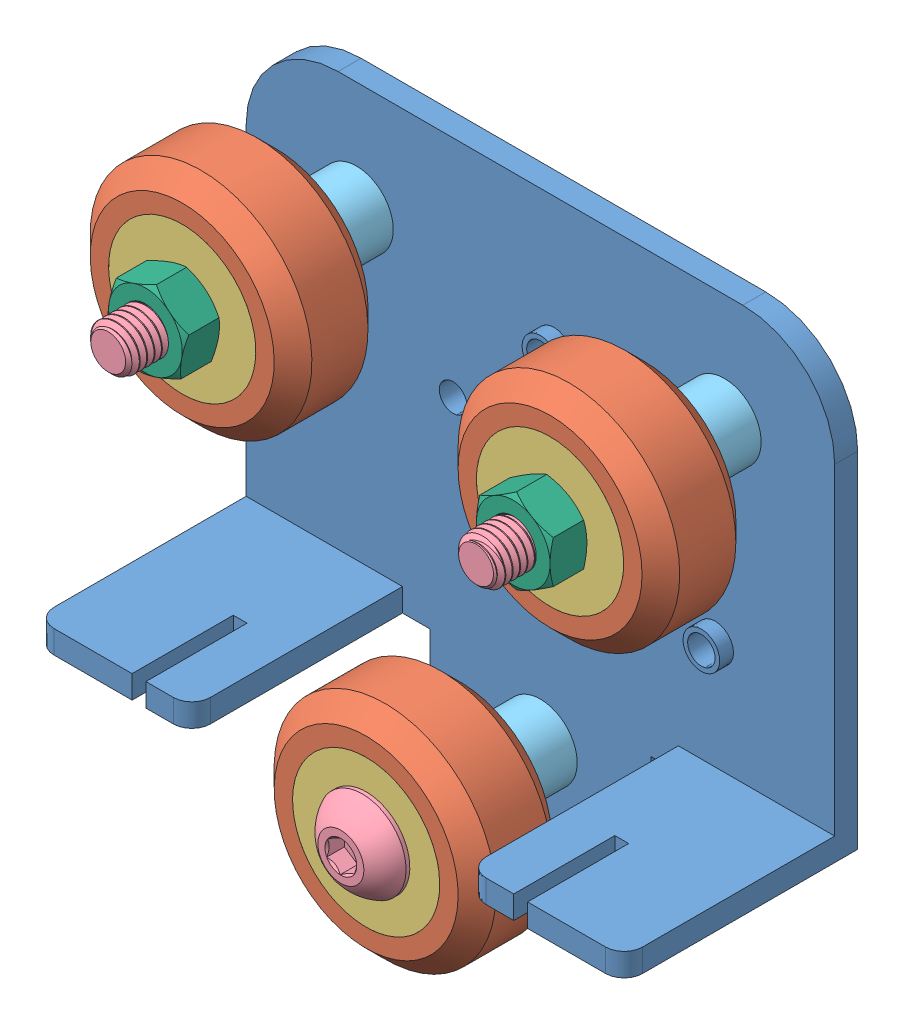
SolidWorks assembly extruder_x_assembly, configuration Default. Lengths in mm.
Overall size (67.79 70.29 30.09).
22 component instances, 6 part files, 12 mates.
Components (placement in the parent):
- E-Plate (Hot end plate)-1: E-Plate (Hot end plate) [Default] at origin size (64 64.1 29.9)
- roller_screw_assembly-4: roller_screw_assembly [2.5mm_gap] at (20 11.85 15.1) x (-1 0 0) z (0 0 -1) size (24.1 24.1 24.37)
  - roller_rubber-1: roller_rubber [Default] at origin size (24.1 24.1 10.2)
  - Bearing for Roller-1: Bearing for Roller [Default] at (0 0 3.1) x (0.970422 -0.241413 0) z (0 0 1) size (16 16 2)
  - Bearing for Roller-2: Bearing for Roller [Default] at (0 0 -5.1) x (0.995973 0.089651 0) z (0 0 1) size (16 16 2)
  - 92095A211_Button Head Hex Drive Screw-1: 92095A211_Button Head Hex Drive Screw [92095A211] at (0 0 19.1) x (-0.966026 0.258445 0) z (0 0 1) size (9.5 9.5 17.99)
  - Roller Spacer-1: Roller Spacer [long] at (0 0 5.1) x (0.816952 -0.576706 0) z (0 0 1) size (8 8 8.75)
- roller_screw_assembly-5: roller_screw_assembly [2.5mm_gap] at (-20 11.85 15.1) x (0.382683 -0.92388 0) z (0 0 -1) size (24.1 24.1 24.37)
  - roller_rubber-1: roller_rubber [Default] at origin size (24.1 24.1 10.2)
  - Bearing for Roller-1: Bearing for Roller [Default] at (0 0 3.1) x (0.970422 -0.241413 0) z (0 0 1) size (16 16 2)
  - Bearing for Roller-2: Bearing for Roller [Default] at (0 0 -5.1) x (0.995973 0.089651 0) z (0 0 1) size (16 16 2)
  - 92095A211_Button Head Hex Drive Screw-1: 92095A211_Button Head Hex Drive Screw [92095A211] at (0 0 19.1) x (-0.966026 0.258445 0) z (0 0 1) size (9.5 9.5 17.99)
  - Roller Spacer-1: Roller Spacer [long] at (0 0 5.1) x (0.816952 -0.576706 0) z (0 0 1) size (8 8 8.75)
- roller_screw_assembly-6: roller_screw_assembly [normal] at (0 -28.35 15.1) x (0.97681 0.214109 0) z (0 0 1) size (24.1 24.1 21.87)
  - roller_rubber-1: roller_rubber [Default] at origin size (24.1 24.1 10.2)
  - Bearing for Roller-1: Bearing for Roller [Default] at (0 0 3.1) x (0.970422 -0.241413 0) z (0 0 1) size (16 16 2)
  - Bearing for Roller-2: Bearing for Roller [Default] at (0 0 -5.1) x (0.995973 0.089651 0) z (0 0 1) size (16 16 2)
  - 92095A211_Button Head Hex Drive Screw-1: 92095A211_Button Head Hex Drive Screw [92095A211] at (0 0 7.85) x (-0.966026 0.258445 0) z (0 0 1) size (9.5 9.5 17.99)
  - Roller Spacer-1: Roller Spacer [long] at (0 0 -13.85) x (0.816952 -0.576706 0) z (0 0 1) size (8 8 8.75)
- 91828A241_18-8 Stainless Steel Hex Nut-4: 91828A241_18-8 Stainless Steel Hex Nut [91828A241] at (0 -28.35 -3.25) x (0.27421 -0.96167 0) z (0 0 1) size (8 9.24 4.46)
- 91828A241_18-8 Stainless Steel Hex Nut-5: 91828A241_18-8 Stainless Steel Hex Nut [91828A241] at (20 11.85 22.2) size (8 9.24 4.46)
- 91828A241_18-8 Stainless Steel Hex Nut-6: 91828A241_18-8 Stainless Steel Hex Nut [91828A241] at (-20 11.85 22.2) x (0.983363 -0.181649 0) z (0 0 1) size (8 9.24 4.46)
Mates (geometry in assembly coordinates):
- Coincident9: coincident anti-aligned: plane of E-Plate (Hot end plate)-1 through (0 -28.35 -1.25) normal (0 0 -1); plane of roller_screw_assembly-4/92095A211_Button Head Hex Drive Screw-1 through (24.5886 13.0776 -1.25) normal (0 0 1)
- Concentric6: concentric anti-aligned: cylinder of E-Plate (Hot end plate)-1 through (20 11.85 1.25) axis (0 0 -1) radius 2.5; cylinder of roller_screw_assembly-4/Roller Spacer-1 through (20 11.85 1.25) axis (0 0 1) radius 4
- Coincident10: coincident anti-aligned: plane of E-Plate (Hot end plate)-1 through (0 -28.35 1.25) normal (0 0 1); plane of roller_screw_assembly-5/Roller Spacer-1 through (-20 11.85 1.25) normal (0 0 -1)
- Concentric7: concentric anti-aligned: cylinder of E-Plate (Hot end plate)-1 through (-20 11.85 1.25) axis (0 0 -1) radius 2.5; cylinder of roller_screw_assembly-5/Roller Spacer-1 through (-20 11.85 1.25) axis (0 0 1) radius 4
- Concentric9: concentric aligned: cylinder of E-Plate (Hot end plate)-1 through (0 -28.35 1.25) axis (0 0 -1) radius 3.6; cylinder of roller_screw_assembly-6/Roller Spacer-1 through (0 -28.35 10) axis (0 0 -1) radius 4
- Coincident11: coincident anti-aligned: plane of E-Plate (Hot end plate)-1 through (0 -28.35 1.25) normal (0 0 1); plane of roller_screw_assembly-6/Roller Spacer-1 through (0 -28.35 1.25) normal (0 0 -1)
- Screw5: screw = 0.8 mm anti-aligned: line of roller_screw_assembly-6/92095A211_Button Head Hex Drive Screw-1 through (0 -28.35 -19.8213) axis (0 0 1); cone of 91828A241_18-8 Stainless Steel Hex Nut-4 through (0 -28.35 -1.25) axis (0 0 -1)
- Coincident12: coincident anti-aligned: plane of E-Plate (Hot end plate)-1 through (0 -28.35 -1.25) normal (0 0 -1); plane of 91828A241_18-8 Stainless Steel Hex Nut-4 through (1.124 -23.8701 -1.25) normal (0 0 1)
- Screw6: screw = 0.8 mm anti-aligned: line of roller_screw_assembly-5/92095A211_Button Head Hex Drive Screw-1 through (-20 11.85 38.7713) axis (0 0 -1); cone of 91828A241_18-8 Stainless Steel Hex Nut-6 through (-20 11.85 20.2) axis (0 0 1)
- Coincident13: coincident anti-aligned: plane of roller_screw_assembly-5/Bearing for Roller-2 through (-20 11.85 20.2) normal (0 0 1); plane of 91828A241_18-8 Stainless Steel Hex Nut-6 through (-23.514 14.8476 20.2) normal (0 0 -1)
- Coincident14: coincident anti-aligned: plane of roller_screw_assembly-4/Bearing for Roller-2 through (20 11.85 20.2) normal (0 0 1); plane of 91828A241_18-8 Stainless Steel Hex Nut-5 through (16 14.1594 20.2) normal (0 0 -1)
- Screw7: screw = 0.8 mm aligned: line of roller_screw_assembly-4/92095A211_Button Head Hex Drive Screw-1 through (20 11.85 38.7713) axis (0 0 -1); cone of 91828A241_18-8 Stainless Steel Hex Nut-5 through (20 11.85 24.2) axis (0 0 -1)
